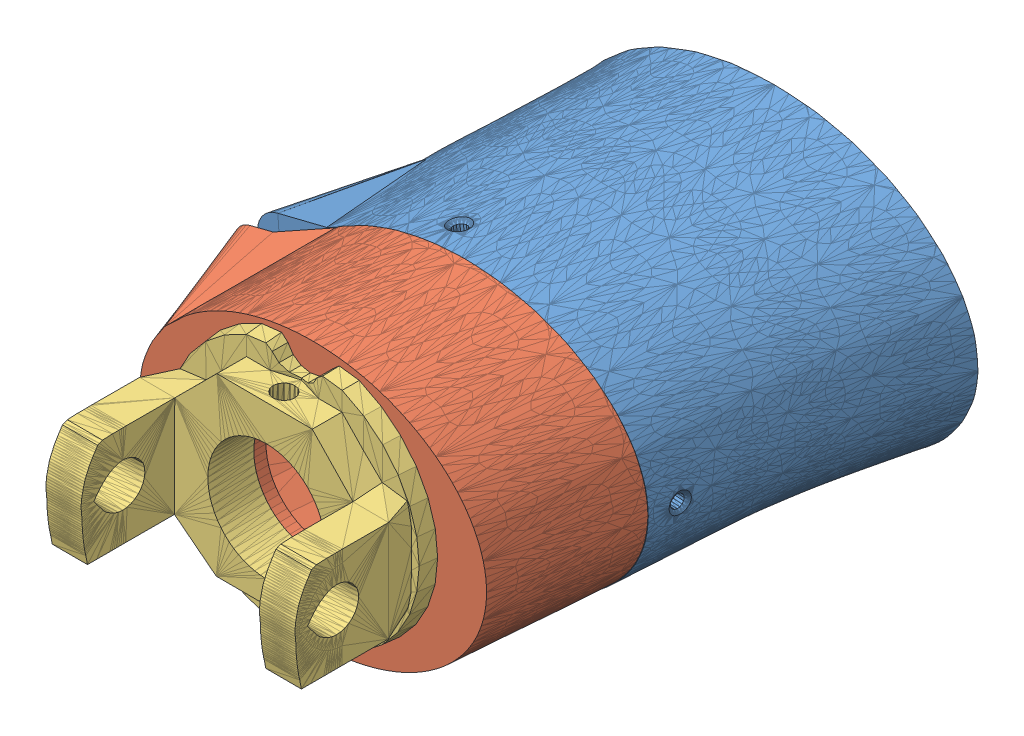
SolidWorks assembly Fixed Wrist, configuration Default. Lengths in mm.
Overall size (80.76 54.04 107.91).
3 component instances, 3 part files, 11 mates.
Components (placement in the parent):
- Rotawrist1V4-1: Rotawrist1V4 [Default] at (-41.5785 2.8378 -7.6893) size (78.57 52.81 54.52)
- RotaWrist2V3-1: RotaWrist2V3 [Default] at (-44.0484 3.5992 74.4289) x (-0.999998 0.000853 -0.001889) z (0.001889 0.000054 -0.999998) size (71.94 48.58 37.95)
- RotaWrist3V3-1: RotaWrist3V3 [Default] at (-43.4074 4.3051 74.4302) x (0.999995 -0.002526 0.001889) z (-0.001889 -0.000054 0.999998) size (47.2 44.33 25.74)
Mates (geometry in assembly coordinates):
- Coincident1: coincident anti-aligned: plane of Rotawrist1V4-1 through (-41.5786 2.8378 46.8299) normal (-0.000002 0 1); plane of RotaWrist2V3-1
- Concentric1: concentric anti-aligned: circle of RotaWrist2V3-1; circle of RotaWrist3V3-1
- Coincident5: coincident anti-aligned: plane of RotaWrist2V3-1 through (-44.0484 3.5992 74.4289) normal (-0.001889 -0.000054 0.999998); plane of RotaWrist3V3-1 through (-43.4074 4.3051 74.4302) normal (0.001889 0.000054 -0.999998)
- Coincident6: coincident anti-aligned: line of RotaWrist2V3-1 through (-62.996 5.011 74.3932) axis (0.999995 -0.002526 0.001889); line of RotaWrist3V3-1 through (-42.6838 4.9597 74.4316) axis (-0.999995 0.002526 -0.001889)
- Coincident8: coincident aligned: line of Rotawrist1V4-1 through (-27.8059 4.7661 46.8298) axis (-1 0 0); line of RotaWrist2V3-1 through (-42.5964 4.7661 46.8298) axis (-1 0 0)
- Parallel8: parallel: plane of Rotawrist1V4-1 through (-41.5786 2.8378 46.8299) normal (-0.000002 0 1); plane of RotaWrist2V3-1
- Coincident10: coincident: line of Rotawrist1V4-1 through (-8.4112 2.8883 41.2767) axis (-0.997759 0.006985 -0.066548); line of RotaWrist2V3-1 through (-13.6906 2.9253 40.9246) axis (0.997759 -0.006985 0.066548)
- Coincident11: coincident: line of Rotawrist1V4-1 through (-47.6235 -17.983 41.253) axis (-0.162031 -0.986786 0.000009); line of RotaWrist2V3-1 through (-47.1988 -15.3863 41.2778) axis (-0.162031 -0.986786 0.000009)
- Coincident14: coincident: line of Rotawrist1V4-1 through (-47.6235 -17.983 41.253) axis (-0.162031 -0.986786 0.000009); point of RotaWrist2V3-1
- Coincident15: coincident: line of Rotawrist1V4-1 through (-48.3547 24.7181 41.2531) axis (-0.143328 0.989675 -0.000045); point of RotaWrist2V3-1
- Coincident16: coincident: line of Rotawrist1V4-1 through (-8.4112 2.8883 41.2767) axis (-0.997759 0.006985 -0.066548); point of RotaWrist2V3-1
